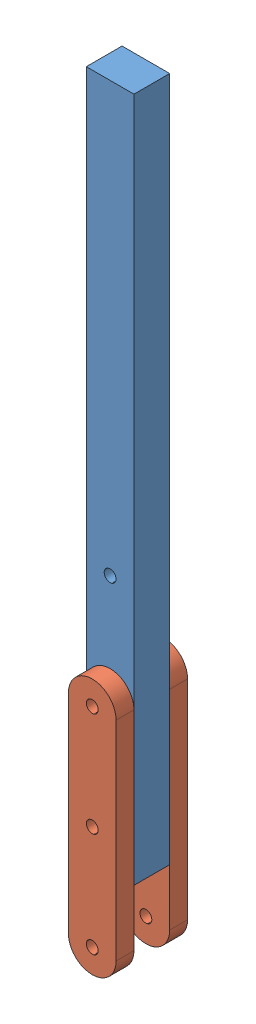
SolidWorks assembly short_spoke_assem, configuration Default. Lengths in mm.
Overall size (8 128.5 12).
3 component instances, 2 part files, 6 mates.
Components (placement in the parent):
- short_spoke-1: short_spoke [Default] at (-4.9578 -5.2417 91.4004) size (8 115 6)
- sopke_part-1: sopke_part [Default] at (67.9692 -18.3463 100.4004) x (-1 0 0) z (0 0 -1) size (8 43 3)
- sopke_part-2: sopke_part [Default] at (67.9692 -18.3463 91.4004) x (-1 0 0) z (0 0 -1) size (8 43 3)
Mates (geometry in assembly coordinates):
- Coincident1: coincident: plane of short_spoke-1 through (-4.9578 -5.2417 97.4004) normal (0 0 1); plane of sopke_part-1 through (32.1755 27.3437 97.4004) normal (0 0 -1)
- Concentric1: concentric: cylinder of short_spoke-1 through (32.1755 27.3437 97.4004) axis (0 0 -1) radius 1; cylinder of sopke_part-1 through (32.1755 27.3437 97.4004) axis (0 0 1) radius 1
- Concentric2: concentric anti-aligned: cylinder of short_spoke-1 through (32.1755 9.8437 97.4004) axis (0 0 -1) radius 1; cylinder of sopke_part-1 through (32.1755 9.8437 97.4004) axis (0 0 1) radius 1
- Coincident4: coincident: plane of short_spoke-1 through (-4.9578 -5.2417 91.4004) normal (0 0 -1); plane of sopke_part-2 through (32.1755 27.3437 91.4004) normal (0 0 1)
- Concentric3: concentric: cylinder of short_spoke-1 through (32.1755 27.3437 97.4004) axis (0 0 -1) radius 1; cylinder of sopke_part-2 through (32.1755 27.3437 88.4004) axis (0 0 1) radius 1
- Concentric4: concentric anti-aligned: cylinder of short_spoke-1 through (32.1755 9.8437 97.4004) axis (0 0 -1) radius 1; cylinder of sopke_part-2 through (32.1755 9.8437 88.4004) axis (0 0 1) radius 1
